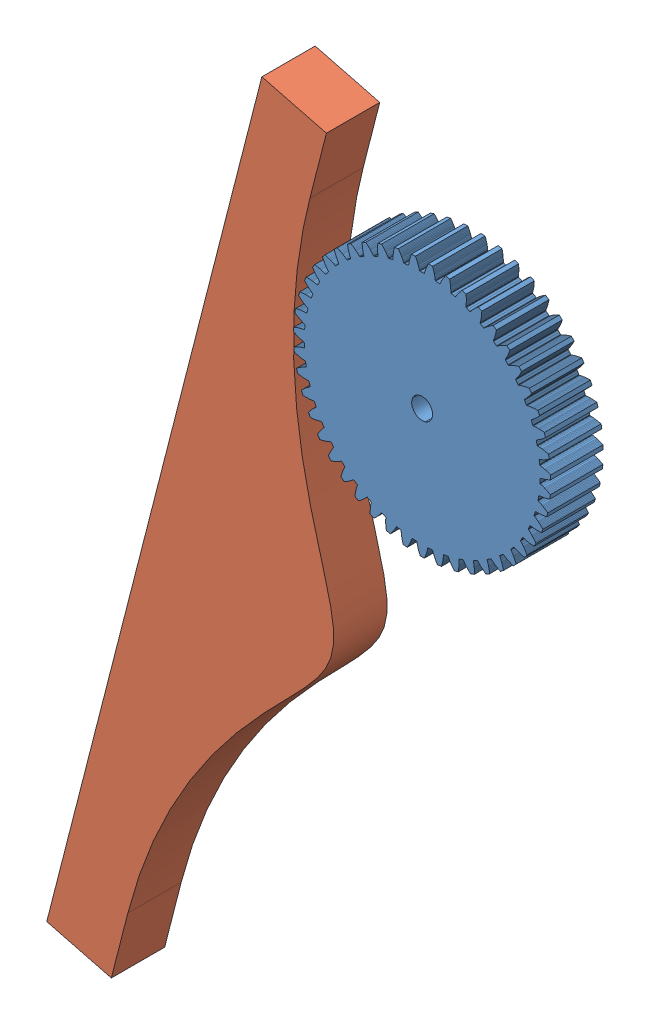
SolidWorks assembly Assem1, configuration Default. Lengths in mm.
Overall size (104.43 168.55 10.16).
2 component instances, 2 part files, 2 mates.
Components (placement in the parent):
- progressive steering gear v2.1-1: progressive steering gear v2.1 [Default] at (9.6736 62.4925 23.008) x (0.449704 0.893178 0) z (0 0 1) size (49.02 49.02 10)
- progressive steering rack v2.1-1: progressive steering rack v2.1 [Default] at (13.8202 31.5707 22.848) x (0.248305 0.968682 0) z (0 0 1) size (165.04 34.94 10.16)
Mates (geometry in assembly coordinates):
- Tangent1: tangent: circle of progressive steering gear v2.1-1; curve of progressive steering rack v2.1-1
- Parallel1: parallel aligned: plane of progressive steering gear v2.1-1 through (9.6736 62.4925 33.008) normal (0 0 1); plane of progressive steering rack v2.1-1 through (13.8202 31.5707 33.008) normal (0 0 1)
